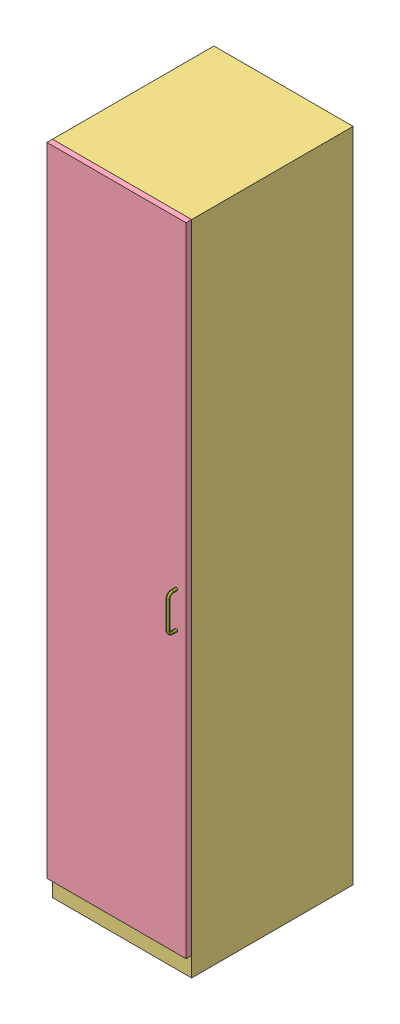
SolidWorks assembly PAX-L, configuration Standard. Lengths in mm.
Overall size (500 2360 635).
11 component instances, 7 part files, 33 mates.
Components (placement in the parent):
- KOMPLEMENT-Regalbode-2: KOMPLEMENT-Regalbode [Standard] at (250 790 295) size (480 10 570)
- KOMPLEMENT-Regalbode-3: KOMPLEMENT-Regalbode [Standard] at (250 940 295) size (480 10 570)
- KOMPLEMENT-Kleiderstange-1: KOMPLEMENT-Kleiderstange [Standard] at (10 2235 325) size (480 50 30)
- Pax-Korpus-Kleiderschrank-236-1: Pax-Korpus-Kleiderschrank-236 [Standard] at (250 0 290) size (500 2360 580)
- BALLSTAD-Tür-229-1: BALLSTAD-Tür-229 [Standard] at (250 1215 580) size (500 2290 20)
- KOMPLIMENT-Schublade-1: KOMPLIMENT-Schublade [Standard] at (250 610 295) size (480 160 570)
- KOMPLIMENT-Schublade-2: KOMPLIMENT-Schublade [Standard] at (250 430 295) size (480 160 570)
- KOMPLIMENT-Schublade-4: KOMPLIMENT-Schublade [Standard] at (250 250 295) size (480 160 570)
- KOMPLEMENT-Regalbode-4: KOMPLEMENT-Regalbode [Standard] at (250 1090 295) size (480 10 570)
- KOMPLEMENT-Netzdrahtkorb-1: KOMPLEMENT-Netzdrahtkorb [Standard] at (250 230 295) size (480 160 570)
- ATTEST-1: ATTEST [Standard] at (460 1139 600) x (0 1 0) z (1 0 0) size (138 35 10)
Mates (geometry in assembly coordinates):
- Abstand3: distance = 20 mm anti-aligned: plane of KOMPLIMENT-Schublade-1 through (250 770 295) normal (0 1 0); plane of KOMPLEMENT-Regalbode-2 through (250 790 295) normal (0 -1 0)
- Deckungsgleich1: coincident anti-aligned: plane of KOMPLEMENT-Regalbode-3 through (10 1101.978 10) normal (0 0 -1); plane of Pax-Korpus-Kleiderschrank-236-1 through (10 2350 10) normal (0 0 1)
- Deckungsgleich2: coincident anti-aligned: plane of KOMPLEMENT-Regalbode-3 through (490 1101.978 580) normal (1 0 0); plane of Pax-Korpus-Kleiderschrank-236-1 through (490 2350 10) normal (-1 0 0)
- Deckungsgleich3: coincident anti-aligned: plane of KOMPLEMENT-Kleiderstange-1 through (490 2235 325) normal (1 0 0); plane of Pax-Korpus-Kleiderschrank-236-1 through (490 2350 10) normal (-1 0 0)
- Abstand7: distance = 300 mm anti-aligned: plane of Pax-Korpus-Kleiderschrank-236-1 through (10 2350 10) normal (0 0 1); plane of KOMPLEMENT-Kleiderstange-1 through (470 2250 310) normal (0 0 -1)
- Deckungsgleich6: coincident anti-aligned: plane of Pax-Korpus-Kleiderschrank-236-1 through (250 0 290) normal (0 -1 0); plane of assembly through (0 0 0) normal (0 1 0)
- Deckungsgleich7: coincident: line of Pax-Korpus-Kleiderschrank-236-1 through (0 0 0) axis (0 0 1); plane of assembly
- Deckungsgleich8: coincident: line of Pax-Korpus-Kleiderschrank-236-1 through (500 0 0) axis (-1 0 0); plane of assembly
- Deckungsgleich10: coincident anti-aligned: plane of KOMPLEMENT-Regalbode-2 through (10 951.978 10) normal (0 0 -1); plane of Pax-Korpus-Kleiderschrank-236-1 through (10 2350 10) normal (0 0 1)
- Deckungsgleich11: coincident anti-aligned: plane of KOMPLEMENT-Regalbode-2 through (490 800 580) normal (1 0 0); plane of Pax-Korpus-Kleiderschrank-236-1 through (490 2350 10) normal (-1 0 0)
- Deckungsgleich12: coincident anti-aligned: plane of KOMPLIMENT-Schublade-1 through (10 771.978 10) normal (0 0 -1); plane of Pax-Korpus-Kleiderschrank-236-1 through (10 2350 10) normal (0 0 1)
- Deckungsgleich13: coincident anti-aligned: plane of KOMPLIMENT-Schublade-1 through (490 771.978 580) normal (1 0 0); plane of Pax-Korpus-Kleiderschrank-236-1 through (490 2350 10) normal (-1 0 0)
- Deckungsgleich14: coincident aligned: plane of Pax-Korpus-Kleiderschrank-236-1 through (0 10 580) normal (-1 0 0); plane of BALLSTAD-Tür-229-1 through (0 70 600) normal (-1 0 0)
- Deckungsgleich15: coincident anti-aligned: plane of Pax-Korpus-Kleiderschrank-236-1 through (0 10 580) normal (0 0 1); plane of BALLSTAD-Tür-229-1 through (250 1215 580) normal (0 0 -1)
- Deckungsgleich16: coincident aligned: plane of Pax-Korpus-Kleiderschrank-236-1 through (250 2360 290) normal (0 1 0); plane of BALLSTAD-Tür-229-1 through (0 2360 600) normal (0 1 0)
- Abstand10: distance = 100 mm anti-aligned: plane of KOMPLEMENT-Kleiderstange-1 through (470 2250 340) normal (0 1 0); plane of Pax-Korpus-Kleiderschrank-236-1 through (250 2350 290) normal (0 -1 0)
- Abstand12: distance = 140 mm anti-aligned: plane of KOMPLEMENT-Regalbode-2 through (250 800 295) normal (0 1 0); plane of KOMPLEMENT-Regalbode-3 through (250 940 295) normal (0 -1 0)
- Deckungsgleich20: coincident anti-aligned: plane of Pax-Korpus-Kleiderschrank-236-1 through (10 2350 10) normal (0 0 1); plane of KOMPLIMENT-Schublade-2 through (10 591.978 10) normal (0 0 -1)
- Deckungsgleich22: coincident anti-aligned: plane of Pax-Korpus-Kleiderschrank-236-1 through (10 2350 10) normal (0 0 1); plane of KOMPLIMENT-Schublade-4 through (10 260 10) normal (0 0 -1)
- Deckungsgleich24: coincident anti-aligned: plane of Pax-Korpus-Kleiderschrank-236-1 through (490 2350 10) normal (-1 0 0); plane of KOMPLIMENT-Schublade-2 through (490 591.978 580) normal (1 0 0)
- Deckungsgleich25: coincident anti-aligned: plane of Pax-Korpus-Kleiderschrank-236-1 through (490 2350 10) normal (-1 0 0); plane of KOMPLIMENT-Schublade-4 through (490 411.978 580) normal (1 0 0)
- Abstand13: distance = 20 mm anti-aligned: plane of KOMPLIMENT-Schublade-2 through (250 590 295) normal (0 1 0); plane of KOMPLIMENT-Schublade-1 through (250 610 295) normal (0 -1 0)
- Abstand14: distance = 20 mm anti-aligned: plane of KOMPLIMENT-Schublade-4 through (250 410 295) normal (0 1 0); plane of KOMPLIMENT-Schublade-2 through (250 430 295) normal (0 -1 0)
- Abstand17: distance = 140 mm anti-aligned: plane of KOMPLEMENT-Regalbode-3 through (250 950 295) normal (0 1 0); plane of KOMPLEMENT-Regalbode-4 through (250 1090 295) normal (0 -1 0)
- Deckungsgleich32: coincident anti-aligned: plane of Pax-Korpus-Kleiderschrank-236-1 through (490 2350 10) normal (-1 0 0); plane of KOMPLEMENT-Regalbode-4 through (490 1251.978 580) normal (1 0 0)
- Deckungsgleich33: coincident anti-aligned: plane of Pax-Korpus-Kleiderschrank-236-1 through (10 2350 10) normal (0 0 1); plane of KOMPLEMENT-Regalbode-4 through (10 1251.978 10) normal (0 0 -1)
- Deckungsgleich34: coincident: plane of Pax-Korpus-Kleiderschrank-236-1 through (490 2350 10) normal (-1 0 0); line of KOMPLEMENT-Netzdrahtkorb-1 through (490 230 580) axis (0 0 -1)
- Deckungsgleich35: coincident: plane of Pax-Korpus-Kleiderschrank-236-1 through (10 2350 10) normal (0 0 1); line of KOMPLEMENT-Netzdrahtkorb-1 through (490 230 10) axis (-1 0 0)
- Deckungsgleich36: coincident anti-aligned: plane of Pax-Korpus-Kleiderschrank-236-1 through (250 70 290) normal (0 1 0); plane of KOMPLEMENT-Netzdrahtkorb-1 through (250 70 295) normal (0 -1 0)
- Abstand18: distance = 20 mm anti-aligned: plane of KOMPLIMENT-Schublade-4 through (250 250 295) normal (0 -1 0); plane of KOMPLEMENT-Netzdrahtkorb-1 through (250 230 295) normal (0 1 0)
- Deckungsgleich38: coincident: plane of BALLSTAD-Tür-229-1 through (250 1215 600) normal (0 0 1); plane of ATTEST-1 through (470 1198 600) normal (0 0 -1)
- Abstand19: distance = 30 mm: line of ATTEST-1 through (470 1188 630) axis (0 -1 0); plane of BALLSTAD-Tür-229-1 through (500 70 600) normal (1 0 0)
- Abstand20: distance = 1000 mm: line of ATTEST-1 through (465 1070 600) axis (0 0 1); plane of BALLSTAD-Tür-229-1 through (0 70 600) normal (0 -1 0)
